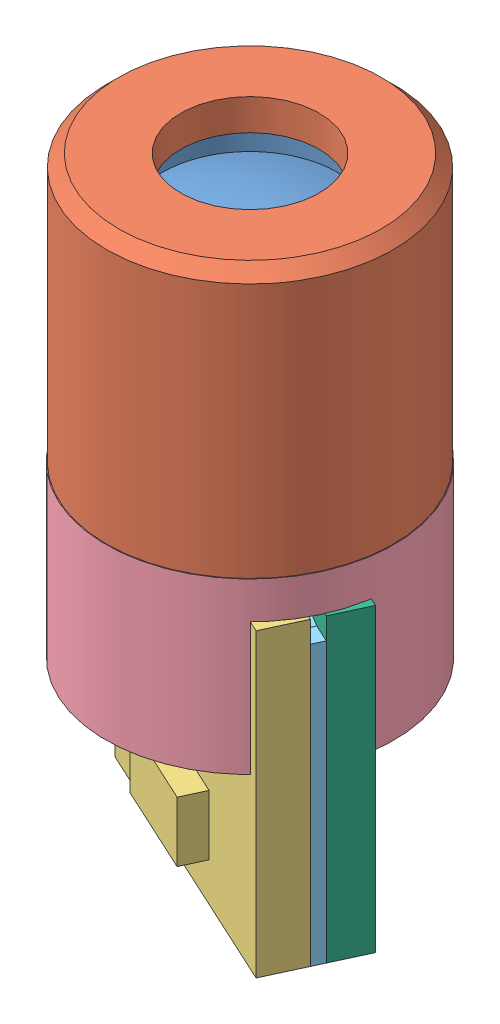
SolidWorks assembly Diode Assembly, configuration Default. Lengths in mm.
Overall size (8.29 12.57 8.29).
6 component instances, 6 part files, 13 mates.
Components (placement in the parent):
- Lens-1: Lens [Default] at (1.6673 2.1484 3.4803) size (4.86 2.14 4.86)
- Lens Nut-1: Lens Nut [Default] at (1.6673 -0.8116 3.4803) x (0.569728 0 -0.821833) z (0.821833 0 0.569728) size (5.96 5.57 5.96)
- N-Board-1: N-Board [Default] at (1.6418 -4.7066 3.6668) x (0.907897 0 0.419194) z (0 -1 0) size (6 1.35 6.25)
- Module-1: Module [Default] at (1.6673 -4.3316 3.4803) x (-0.419194 0 0.907897) z (-0.907897 0 -0.419194) size (5.99 6.07 6.01)
- Diode Interface Board-1: Diode Interface Board [Default] at (1.6418 -4.7066 3.6668) x (0 1 0) z (-0.907897 0 -0.419194) size (6.25 0.25 6)
- P-Board-1: P-Board [Default] at (1.7466 -4.7066 3.4398) x (0 1 0) z (-0.907897 0 -0.419194) size (6.25 0.77 6)
Mates (geometry in assembly coordinates):
- Coincident1: coincident: plane of Diode Interface Board-1 through (1.7466 -4.7066 3.4398) normal (0.419194 0 -0.907897); plane of P-Board-1 through (1.7466 -4.7066 3.4398) normal (-0.419194 0 0.907897)
- Coincident2: coincident: plane of Diode Interface Board-1 through (-0.9771 -7.8316 2.1823) normal (-0.907897 0 -0.419194); plane of P-Board-1 through (-0.6795 -7.8316 1.5376) normal (-0.907897 0 -0.419194)
- Coincident3: coincident: plane of Diode Interface Board-1 through (4.4702 -7.8316 4.6974) normal (0 -1 0); plane of P-Board-1 through (4.7679 -7.8316 4.0528) normal (0 -1 0)
- Coincident4: coincident: plane of N-Board-1 through (1.6418 -4.7066 3.6668) normal (0.419194 0 -0.907897); plane of Diode Interface Board-1 through (1.6418 -4.7066 3.6668) normal (-0.419194 0 0.907897)
- Coincident5: coincident: plane of N-Board-1 through (-1.4382 -7.8316 3.1809) normal (0 -1 0); plane of P-Board-1 through (4.7679 -7.8316 4.0528) normal (0 -1 0)
- Coincident6: coincident: plane of N-Board-1 through (4.0091 -1.5816 5.6961) normal (0.907897 0 0.419194); plane of P-Board-1 through (4.7679 -7.8316 4.0528) normal (0.907897 0 0.419194)
- Coincident7: coincident: plane of Lens-1 through (4.0973 4.0884 3.4803) normal (0 1 0); plane of Lens Nut-1 through (1.6673 4.0884 3.4803) normal (0 -1 0)
- Concentric1: concentric: cylinder of Lens-1 through (1.6673 2.1484 3.4803) axis (0 -1 0) radius 2.43; cylinder of Lens Nut-1 through (1.6673 4.7384 3.4803) axis (0 -1 0) radius 2.98
- Coincident8: coincident: plane of Module-1 through (4.7599 -1.5816 3.983) normal (0 -1 0); plane of Diode Interface Board-1 through (2.836 -1.5816 3.9429) normal (0 1 0)
- Coincident9: coincident: plane of Module-1 through (4.7599 -4.3316 3.983) normal (-0.419194 0 0.907897); plane of P-Board-1 through (2.0693 -4.7066 2.7408) normal (0.419194 0 -0.907897)
- Distance2: distance = 0.05 mm: plane of N-Board-1 through (-1.4382 -1.5816 3.1809) normal (-0.907897 0 -0.419194); cylinder of Module-1 through (1.6673 -0.8116 3.4803) axis (0 -1 0) radius 2.995
- Concentric2: concentric: cylinder of Lens Nut-1 through (1.6673 4.7384 3.4803) axis (0 -1 0) radius 2.98; cylinder of Module-1 through (1.6673 -0.8116 3.4803) axis (0 -1 0) radius 2.995
- Coincident10: coincident: plane of Lens Nut-1 through (1.6673 -0.8116 3.4803) normal (0 -1 0); plane of Module-1 through (1.6673 -0.8116 3.4803) normal (0 1 0)
